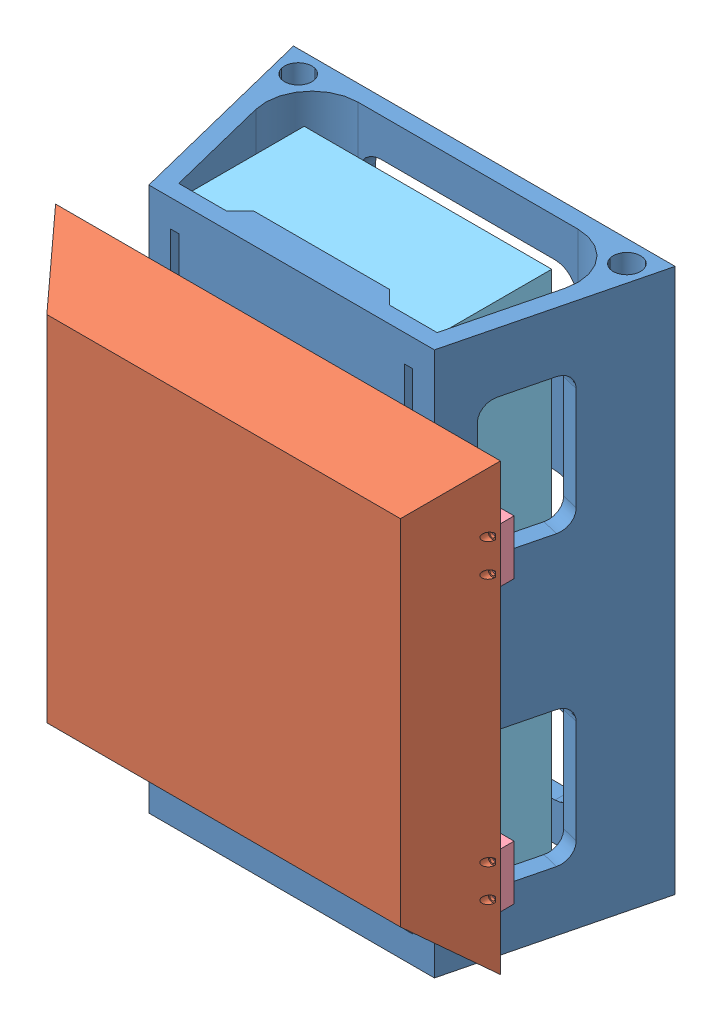
SolidWorks assembly NEW_BatteryBox_assembly, configuration Default. Lengths in mm.
Overall size (163.57 200 95.84).
7 component instances, 5 part files, 6 mates.
Components (placement in the parent):
- New_batteryBox-1: New_batteryBox [Default] at origin size (140.32 200 70.84)
- bluetooth_radome_ASSEMBLY-1: bluetooth_radome_ASSEMBLY [Default] at (2.2223 100.002 60.0359) x (0 1 0) z (-1 0 0) size (163.56 25 163.57)
  - aircraft_BLE_radome-1: aircraft_BLE_radome [Default] at origin size (163.56 20 163.56)
  - BLE_Soc_stand-in-1: BLE_Soc_stand-in [Default] at (-0.0407 5.1 -0.05) size (114.5 5 114.5)
  - radome_crossbar-1: radome_crossbar [Default] at (-51.782 20 0.003) x (0 0 -1) z (1 0 0) size (163.57 5 20)
  - radome_crossbar-2: radome_crossbar [Default] at (51.782 20 0.003) x (0 0 -1) z (1 0 0) size (163.57 5 20)
- new_battery-1: new_battery [Default] at (2.344 100.25 -14.9641) x (0 1 0) z (0 0 1) size (194 91 44)
Mates (geometry in assembly coordinates):
- Coincident1: coordinate: point of New_batteryBox-1
- Concentric8: concentric anti-aligned: circle of New_batteryBox-1; cylinder of bluetooth_radome_ASSEMBLY-1/radome_crossbar-1 through (-22.7807 48.22 45.0359) axis (0 0 -1) radius 1.5
- Parallel1: parallel aligned: line of New_batteryBox-1 through (-50.2807 200 35.0359) axis (1 0 0); line of bluetooth_radome_ASSEMBLY-1/radome_crossbar-2 through (-79.5657 161.784 35.0359) axis (1 0 0)
- Coincident4: coincident anti-aligned: plane of New_batteryBox-1 through (-50.2807 200 35.0359) normal (0 0 1); plane of bluetooth_radome_ASSEMBLY-1/radome_crossbar-2 through (2.2193 151.784 35.0359) normal (0 0 -1)
- Distance1: distance = 1 mm anti-aligned: plane of new_battery-1 through (47.844 3.25 29.0359) normal (0 -1 0); plane of New_batteryBox-1 through (32.2193 2.25 24.0359) normal (0 1 0)
- Coincident6: coincident anti-aligned: plane of New_batteryBox-1 through (-45.2807 200 29.0359) normal (0 0 -1); plane of new_battery-1 through (2.344 100.25 29.0359) normal (0 0 1)
